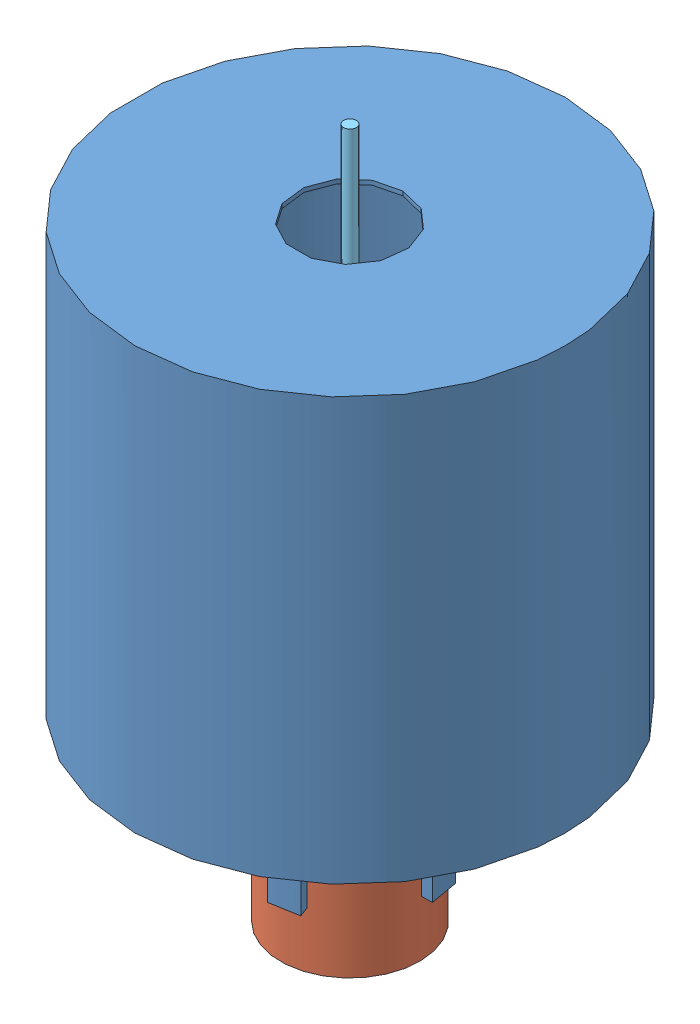
SolidWorks assembly kapak, configuration Default. Lengths in mm.
Overall size (102 163.6 102).
8 component instances, 5 part files, 18 mates.
Components (placement in the parent):
- Hazne-1: Hazne [Default] at origin size (102 130 102)
- kapak-1: kapak [Default] at (0 -43.6 0) x (-0.997047 0 0.076796) z (-0.076796 0 -0.997047) size (33 20 33)
- hareketli dişli aktarma-2: hareketli dişli aktarma [Default] at (0 10.1526 0) x (-0.700882 0 -0.713277) z (0.713277 0 -0.700882) size (27 59 7.5)
- hareketli dişli aktarma-1: hareketli dişli aktarma [Default] at (0 10.1526 0) x (0.700882 0 0.713277) z (-0.713277 0 0.700882) size (27 59 7.5) (hidden)
- sabit dişli aktarma-1: sabit dişli aktarma [Default] at (0 12.9 0) x (-0.700882 0 -0.713277) z (0.713277 0 -0.700882) size (10.02 10 10.02)
- sabit dişli aktarma-2: sabit dişli aktarma [Default] at (0 65 0) x (-0.008765 0 0.999962) z (0.999962 0 0.008765) size (10.02 10 10.02)
- mil-1: mil [Default] at (0 -42.1 0) x (-0.309571 0 -0.950876) z (0.950876 0 -0.309571) size (3 60 3)
- mil-2: mil [Default] at (0 120 0) x (-0.864661 0 -0.502356) z (-0.502356 0 0.864661) size (3 60 3)
Mates (geometry in assembly coordinates):
- Coincident1: coincident anti-aligned: plane of hareketli dişli aktarma-2 through (9.4619 8.1526 9.6292) normal (0.713277 0 -0.700882); plane of hareketli dişli aktarma-1 through (-9.4619 8.1526 -9.6292) normal (-0.713277 0 0.700882)
- Concentric1: concentric anti-aligned: cylinder of hareketli dişli aktarma-2 through (-6.2893 37.6526 -8.5407) axis (-0.713277 0 0.700882) radius 1.5; cylinder of hareketli dişli aktarma-1 through (-8.4292 37.6526 -6.4381) axis (0.713277 0 -0.700882) radius 1.5
- Concentric2: concentric anti-aligned: cylinder of hareketli dişli aktarma-2 through (8.4292 37.6526 6.4381) axis (-0.713277 0 0.700882) radius 1.5; cylinder of hareketli dişli aktarma-1 through (6.2893 37.6526 8.5407) axis (0.713277 0 -0.700882) radius 1.5
- Concentric3: concentric anti-aligned: cylinder of sabit dişli aktarma-1 through (0 22.9 0) axis (0 -1 0) radius 5.1; cylinder of hareketli dişli aktarma-1 through (0 10.1526 0) axis (0 1 0) radius 5.5
- Concentric4: concentric aligned: cylinder of sabit dişli aktarma-1 through (0 17.9 0) axis (0 -1 0) radius 1.5; cylinder of mil-1 through (0 17.9 0) axis (0 -1 0) radius 1.5
- Coincident2: coincident anti-aligned: plane of sabit dişli aktarma-1 through (0 17.9 0) normal (0 -1 0); plane of mil-1 through (0 17.9 0) normal (0 1 0)
- Concentric5: concentric aligned: cylinder of sabit dişli aktarma-2 through (0 60 0) axis (0 1 0) radius 1.5; cylinder of mil-2 through (0 60 0) axis (0 1 0) radius 1.5
- Coincident3: coincident anti-aligned: plane of sabit dişli aktarma-2 through (0 60 0) normal (0 1 0); plane of mil-2 through (0 60 0) normal (0 -1 0)
- Concentric6: concentric aligned: cylinder of hareketli dişli aktarma-2 through (0 10.1526 0) axis (0 1 0) radius 5.5; cylinder of sabit dişli aktarma-2 through (0 55 0) axis (0 1 0) radius 5.1
- Parallel1: parallel anti-aligned: plane of hareketli dişli aktarma-2 through (-1.8999 10.1526 1.3242) normal (0.820402 0 -0.571787); plane of sabit dişli aktarma-2 through (-1.7358 55 1.2098) normal (-0.820402 0 0.571787)
- Parallel2: parallel anti-aligned: plane of hareketli dişli aktarma-2 through (0.3671 10.1526 2.2865) normal (-0.158515 0 -0.987357); plane of sabit dişli aktarma-1 through (0.3354 22.9 2.0891) normal (0.158515 0 0.987357)
- Concentric7: concentric anti-aligned: cylinder of Hazne-1 through (0 100 0) axis (0 -1 0) radius 12.5; cylinder of mil-2 through (0 60 0) axis (0 1 0) radius 1.5
- Concentric8: concentric aligned: cylinder of kapak-1 through (0 -37.1 0) axis (0 -1 0) radius 1.5; cylinder of mil-1 through (0 17.9 0) axis (0 -1 0) radius 1.5
- Coincident6: coincident anti-aligned: plane of kapak-1 through (0 -42.1 0) normal (0 1 0); plane of mil-1 through (0 -42.1 0) normal (0 -1 0)
- LimitDistance1: limit distance = 22.1 mm anti-aligned: plane of kapak-1 through (0 -42.1 0) normal (0 1 0); plane of Hazne-1 through (0 -20 0) normal (0 -1 0)
- LimitDistance2: limit distance = 2.7474 mm anti-aligned: plane of hareketli dişli aktarma-2 through (0 10.1526 0) normal (0 1 0); plane of sabit dişli aktarma-1 through (0 12.9 0) normal (0 -1 0)
- LimitDistance3: limit distance = 0.1526 mm anti-aligned: plane of sabit dişli aktarma-2 through (0 65 0) normal (0 1 0); plane of hareketli dişli aktarma-2 through (0 65.1526 0) normal (0 -1 0)
- Distance5: distance = 20 mm aligned: plane of mil-2 through (0 120 0) normal (0 1 0); plane of Hazne-1 through (0 100 0) normal (0 1 0)
